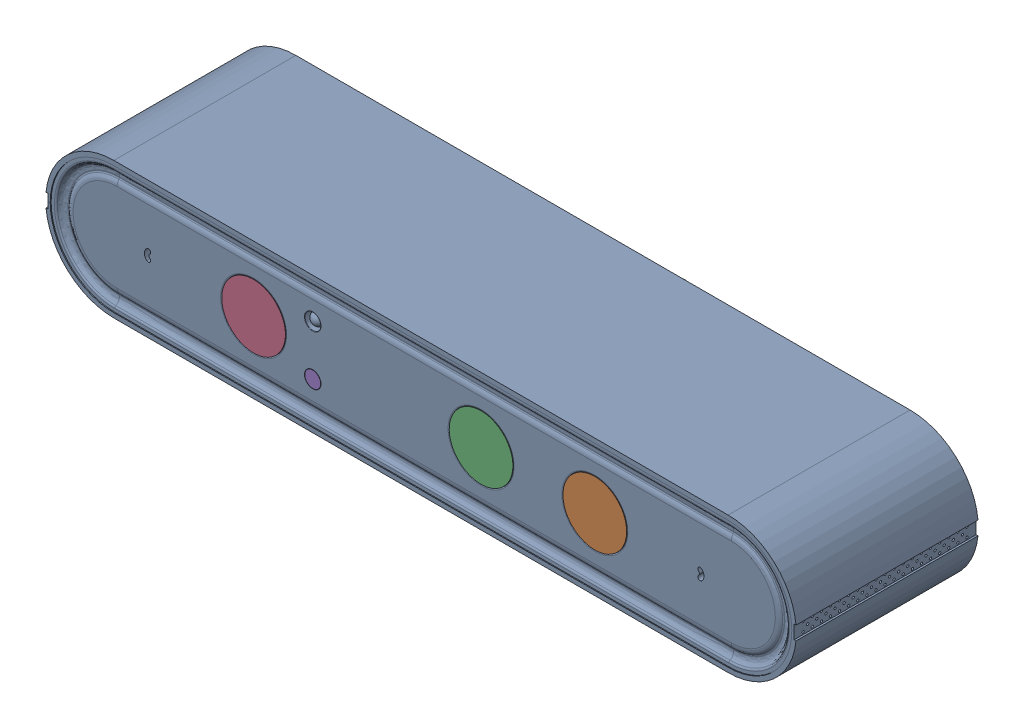
SolidWorks assembly Main_Body, configuration Default. Lengths in mm.
Overall size (164.85 35.05 58.1).
5 component instances, 3 part files, 8 mates.
Components (placement in the parent):
- MainBody-1: MainBody [Default] at origin size (164.85 35.05 58.1)
- Glass1-1: Glass1 [Default] at (72.1398 14.3643 -2.4) x (-0.923728 -0.383049 0) z (0 0 -1) size (14 14 1)
- Glass1-2: Glass1 [Default] at (47.1398 14.3643 -2.4) x (-0.923728 -0.383049 0) z (0 0 -1) size (14 14 1)
- Glass1-3: Glass1 [Default] at (-75 0 0) size (14 14 1)
- SGlass1-1: SGlass1 [Default] at (-49.2381 -9.8042 -2.4) x (-0.923728 -0.383049 0) z (0 0 -1) size (3.5 3.5 1)
Mates (geometry in assembly coordinates):
- Distance1: distance = 1 mm anti-aligned: plane of Glass1-3 through (-37.5 0 -1.7) normal (0 0 -1); plane of MainBody-1 through (-67.5 0 -0.7) normal (0 0 1)
- Concentric1: concentric anti-aligned: cylinder of Glass1-3 through (-37.5 0 -0.7) axis (0 0 -1) radius 7; cylinder of MainBody-1 through (-37.5 0 -2.7) axis (0 0 1) radius 7
- Coincident1: coincident aligned: circle of Glass1-3; plane of SGlass1-1 through (-24.5 -5.5 -0.7) normal (0 0 1)
- Coincident4: coincident aligned: plane of Glass1-2 through (12.5 0 -0.7) normal (0 0 1); plane of Glass1-3 through (-37.5 0 -0.7) normal (0 0 1)
- Coincident5: coincident anti-aligned: circle of Glass1-1; plane of Glass1-3 through (-37.5 0 -0.7) normal (0 0 1)
- Concentric5: concentric aligned: cylinder of MainBody-1 through (-24.5 -5.5 -2.7) axis (0 0 1) radius 1.75; cylinder of SGlass1-1 through (-24.5 -5.5 -1.7) axis (0 0 1) radius 1.75
- Concentric6: concentric aligned: cylinder of MainBody-1 through (12.5 0 -2.7) axis (0 0 1) radius 7; cylinder of Glass1-2 through (12.5 0 -1.7) axis (0 0 1) radius 7
- Concentric7: concentric aligned: cylinder of MainBody-1 through (37.5 0 -2.7) axis (0 0 1) radius 7; cylinder of Glass1-1 through (37.5 0 -1.7) axis (0 0 1) radius 7
